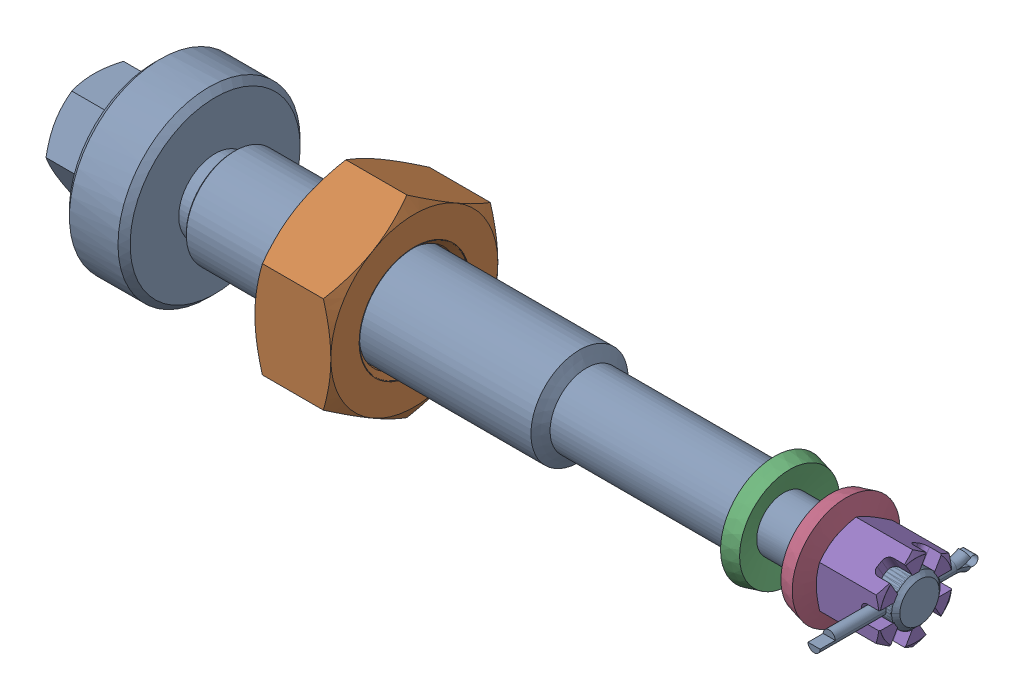
SolidWorks assembly g1_3_1_1_7_2, configuration 默认. Lengths in mm.
Overall size (272.02 63.51 60).
6 component instances, 5 part files, 0 mates.
Components (placement in the parent):
- g1_3_1_1_7-1_2-1: g1_3_1_1_7-1_2 [默认] at origin size (272.02 60 60)
- g1_3_1_1_7-2_2-1: g1_3_1_1_7-2_2 [默认] at (-104.3833 -31.7543 0) x (0 1 0) z (1 0 0) size (63.51 55 25)
- 4x40_gb91_2-1: 4x40_gb91_2 [默认] at (82.0173 -2 29.7543) x (0 0 1) z (-1 -0.000312 0) size (52 6.04 4)
- a35_5_gb1972_2-1: a35_5_gb1972_2 [默认] at (39.2167 0 0) x (0 0.075145 0.997173) z (0 0.997173 -0.075145) size (35.5 7.2 35.5)
- a35_5_gb1972_2-2: a35_5_gb1972_2 [默认] at (62.8167 0 0) x (0 -0.99777 0.066751) z (0 -0.066751 -0.99777) size (35.5 7.2 35.5)
- m16a_gb6178_2-1: m16a_gb6178_2 [默认] at (85.8167 13.8564 0) x (0 -1 0) z (-1 0 0) size (27.71 24 20.8)
